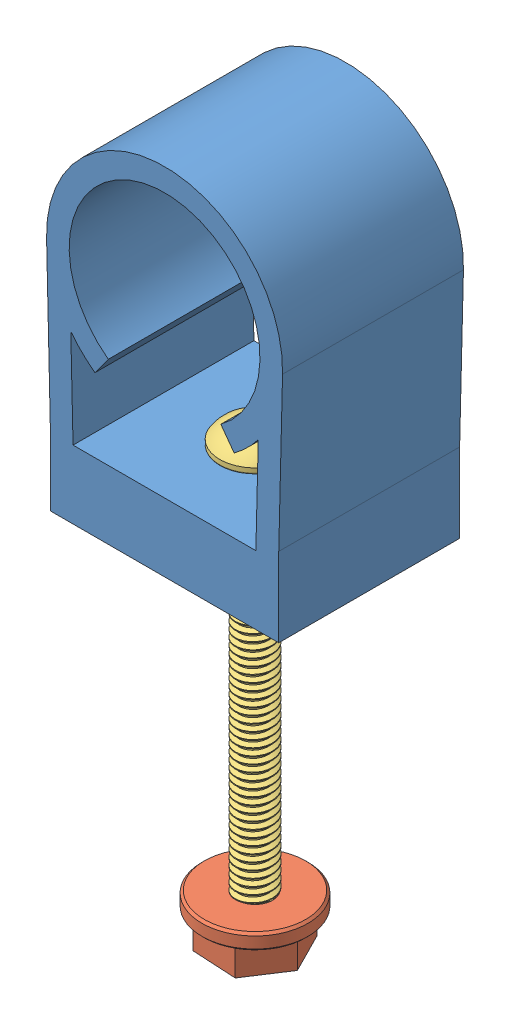
SolidWorks assembly fastener_assembly, configuration Default. Lengths in mm.
Overall size (26.52 80.65 20.32).
3 component instances, 3 part files, 4 mates.
Components (placement in the parent):
- pvc-050-standoff-1: pvc-050-standoff [Default] at (-1.3406 5.3933 19.2211) size (26.52 39.93 20.32)
- hrd-08-32-flng-nut02-1: hrd-08-32-flng-nut02 [Default] at (11.4864 -30.1667 29.3811) x (-0.837169 0 -0.546944) z (-0.546944 0 0.837169) size (11.91 5.16 11.91)
- HRD-008-175-BTN-SS-1: HRD-008-175-BTN-SS [Default] at (11.4864 13.0724 29.3811) size (7.92 46.77 7.92)
Mates (geometry in assembly coordinates):
- Coincident1: coincident anti-aligned: plane of pvc-050-standoff-1 through (1.2046 13.0724 39.5411) normal (0 1 0); plane of HRD-008-175-BTN-SS-1 through (13.6962 13.0724 29.3811) normal (0 -1 0)
- Concentric1: concentric aligned: circle of pvc-050-standoff-1; circle of HRD-008-175-BTN-SS-1
- Distance1: distance = 35.56 mm anti-aligned: plane of hrd-08-32-flng-nut02-1 through (11.4864 -30.1667 29.3811) normal (0 1 0); plane of pvc-050-standoff-1 through (-1.3406 5.3933 39.5411) normal (0 -1 0)
- Concentric2: concentric aligned: circle of hrd-08-32-flng-nut02-1; circle of HRD-008-175-BTN-SS-1
